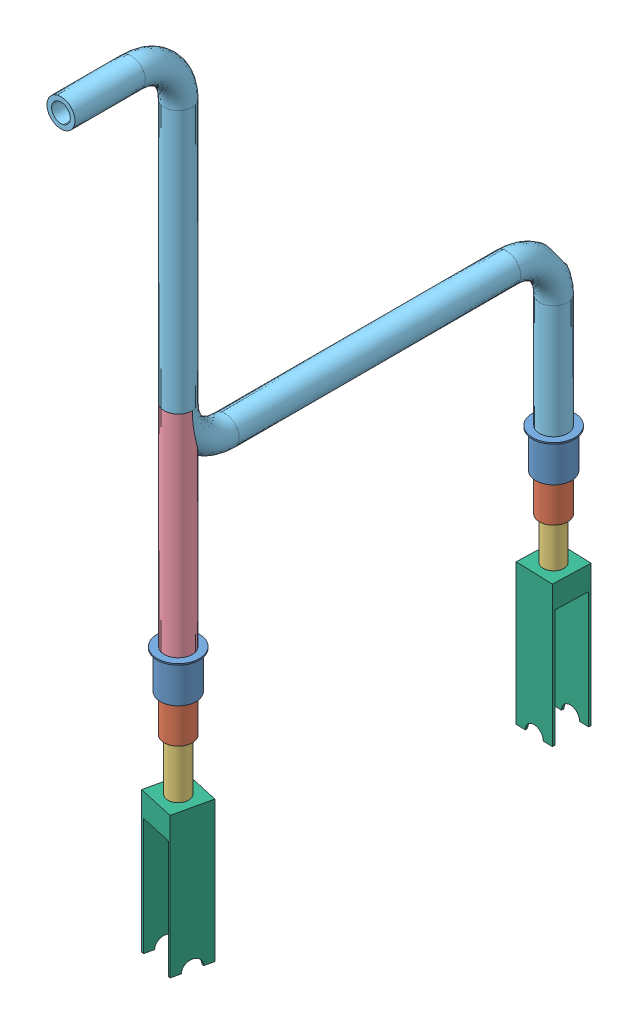
SolidWorks assembly telescope, configuration Default. Lengths in mm.
Overall size (125.2 1712.84 1112.6).
10 component instances, 6 part files, 23 mates.
Components (placement in the parent):
- Part1-1: Part1 [Default] at (-1335.3167 235.5102 -102.0861) x (0 -1 0) z (-0.568138 0 -0.822933) size (83 90 90)
- Part2-1: Part2 [Default] at (-1335.3167 243.7286 -102.0861) x (0 -1 0) z (-0.866706 0 0.498819) size (83 70 70)
- Part3-1: Part3 [Default] at (-1335.3167 362.4799 -102.0861) x (0 -1 0) z (0.343056 0 0.939315) size (120 54 54)
- fra-1: fra [Default] at (-1335.3167 757.6458 697.9139) size (60 450 60)
- frame-1: frame [Default] at (-1335.3167 657.4677 697.9139) size (60 1140 1080)
- Part3-2: Part3 [Default] at (-1335.3167 354.6154 697.9139) x (0 -1 0) z (0.999919 0 0.012744) size (120 54 54)
- Part2-2: Part2 [Default] at (-1335.3167 235.8642 697.9139) x (0 -1 0) z (-0.866706 0 0.498819) size (83 70 70)
- Part1-2: Part1 [Default] at (-1335.3167 227.6458 697.9139) x (0 -1 0) z (-0.568138 0 -0.822933) size (83 90 90)
- rev-1: rev [Default] at (-1374.3634 -115.376 689.2333) x (0.976168 0 0.217017) z (-0.217017 0 0.976168) size (80 300 80)
- rev-2: rev [Default] at (-1336.6338 -87.4278 -62.1077) x (0.032927 0 -0.999458) z (0.999458 0 0.032927) size (80 300 80)
Mates (geometry in assembly coordinates):
- Concentric1: concentric anti-aligned: cylinder of Part1-1 through (-1335.3167 235.5102 -102.0861) axis (0 -1 0) radius 38; cylinder of Part2-1 through (-1335.3167 243.7286 -102.0861) axis (0 1 0) radius 30
- Concentric2: concentric aligned: cylinder of Part2-1 through (-1335.3167 243.7286 -102.0861) axis (0 1 0) radius 30; cylinder of Part3-1 through (-1335.3167 168.4799 -102.0861) axis (0 1 0) radius 22
- LimitDistance1: limit distance = 80 mm aligned: plane of Part2-1 through (-1321.8486 152.5102 -78.685) normal (0 -1 0); plane of Part1-1 through (-1364.1193 232.5102 -82.2012) normal (0 -1 0)
- Concentric3: concentric aligned: cylinder of Part2-1 through (-1335.3167 243.7286 -102.0861) axis (0 1 0) radius 30; cylinder of Part3-1 through (-1335.3167 168.4799 -102.0861) axis (0 1 0) radius 22
- LimitDistance4: limit distance = 3 mm aligned: plane of Part2-1 through (-1321.8486 152.5102 -78.685) normal (0 -1 0); plane of Part3-1 through (-1309.9552 155.5102 -111.3486) normal (0 -1 0)
- Concentric4: concentric aligned: cylinder of fra-1 through (-1335.3167 757.6458 697.9139) axis (0 -1 0) radius 20; circle of frame-1
- Concentric5: concentric aligned: circle of fra-1; cylinder of frame-1 through (-1335.3167 1317.4677 697.9139) axis (0 -1 0) radius 30
- Concentric6: concentric aligned: circle of fra-1; circle of frame-1
- Concentric8: concentric aligned: circle of Part1-1; circle of frame-1
- Concentric9: concentric aligned: circle of Part1-1; circle of frame-1
- Concentric10: concentric aligned: cylinder of Part1-1 through (-1335.3167 235.5102 -102.0861) axis (0 -1 0) radius 38; cylinder of frame-1 through (-1335.3167 557.4677 -102.0861) axis (0 -1 0) radius 30
- LimitDistance5: limit distance = 3 mm aligned: plane of Part2-2 through (-1321.8486 144.6458 721.315) normal (0 -1 0); plane of Part3-2 through (-1334.9726 147.6458 670.9161) normal (0 -1 0)
- LimitDistance6: limit distance = 80 mm aligned: plane of Part2-2 through (-1321.8486 144.6458 721.315) normal (0 -1 0); plane of Part1-2 through (-1364.1193 224.6458 717.7988) normal (0 -1 0)
- Concentric14: concentric anti-aligned: cylinder of Part2-2 through (-1335.3167 235.8642 697.9139) axis (0 1 0) radius 30; cylinder of Part1-2 through (-1335.3167 227.6458 697.9139) axis (0 -1 0) radius 38
- Concentric15: concentric aligned: cylinder of Part3-2 through (-1335.3167 160.6154 697.9139) axis (0 1 0) radius 22; cylinder of Part2-2 through (-1335.3167 235.8642 697.9139) axis (0 1 0) radius 30
- Concentric16: concentric aligned: cylinder of Part3-2 through (-1335.3167 160.6154 697.9139) axis (0 1 0) radius 22; cylinder of Part2-2 through (-1335.3167 235.8642 697.9139) axis (0 1 0) radius 30
- Concentric20: concentric aligned: circle of fra-1; circle of Part1-2
- Lock1: lock: unknown of fra-1; unknown of Part1-2
- Concentric22: concentric aligned: circle of Part3-2; circle of rev-1
- Lock2: lock: unknown of Part3-2; unknown of rev-1
- Concentric29: concentric aligned: circle of Part3-1; circle of rev-2
- Lock3: lock: unknown of Part3-1; unknown of rev-2
- Lock4: lock: unknown of fra-1; unknown of frame-1
